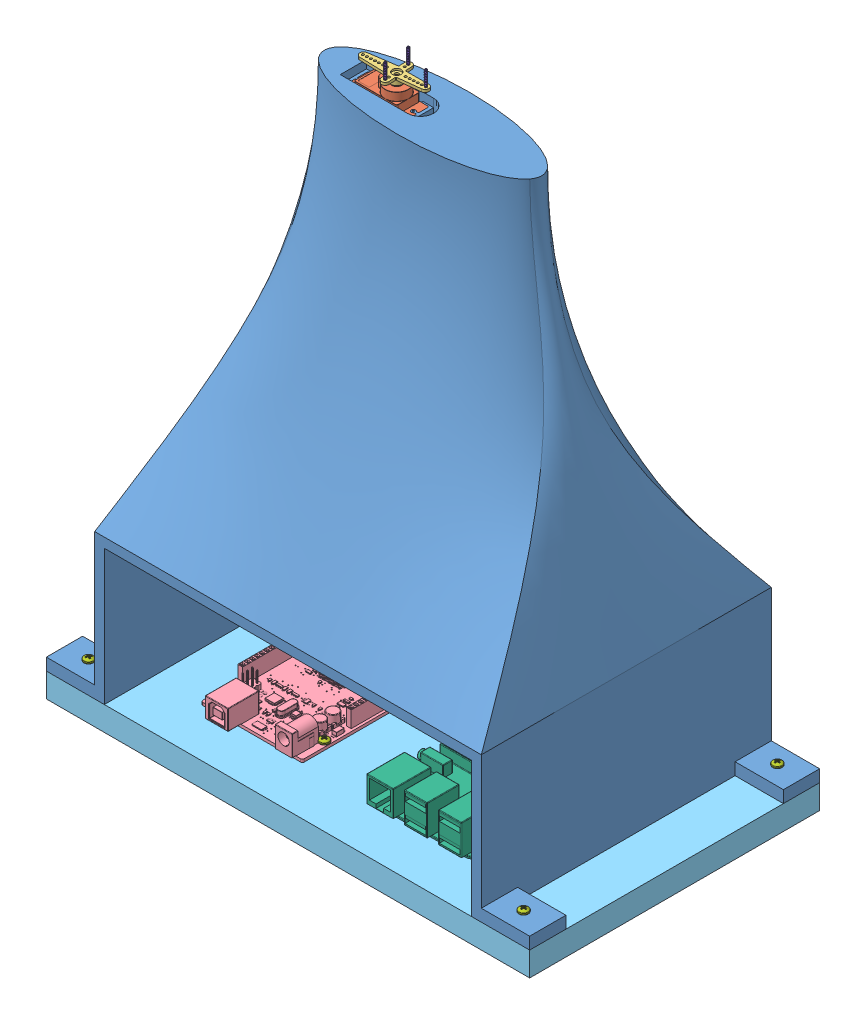
SolidWorks assembly Arm_Assembly, configuration Défaut. Lengths in mm.
Overall size (254 309.43 152.4).
24 component instances, 8 part files, 47 mates.
Components (placement in the parent):
- Bras-1: Bras [Défaut] at (-45.4509 154.1913 381.0005) size (254 279.4 152.4)
- SG90 - Micro Servo Assembly Socle-3: SG90 - Micro Servo Assembly Socle [Default] at (-69.6506 142.242 381.0005) x (-1 0 0) z (0 0 -1) size (37.72 31.75 18.74) (flexible)
  - SG90 - Micro Servo 9g - Tower Pro.1-2: SG90 - Micro Servo 9g - Tower Pro.1 [Peça] at origin size (32.1 29.95 12.4)
  - SG90 - Micro Servo 9g - Tower Pro.4-1: SG90 - Micro Servo 9g - Tower Pro.4 [Peça] at (-5.15 21.1 0) x (0.998205 0 -0.059895) z (0.059895 0 0.998205) size (34.5 3.8 16.7)
- arduinoMega-1: arduinoMega [Detailed] at (-89.9209 -125.2087 382.3105) x (0 0 -1) z (1 0 0) size (108.32 14.5 53.3)
- Base-1: Base [Défaut] at (-172.4509 -137.9087 457.2005) size (254 12.7 152.4)
- Raspberrypimodel-1: Raspberrypimodel [Default] at (1.1691 -125.2087 389.3005) x (0 0 1) z (-1 0 0) size (87.5 17 58)
- 92000A106_18-8 SS METRIC PAN HEAD PHIL MACHINE SCREW-1: 92000A106_18-8 SS METRIC PAN HEAD PHIL MACHINE SCREW [92000A106] at (-65.8109 -133.7087 335.3305) x (1 0 0) z (0 1 0) size (5 5 12.1)
- 92000A106_18-8 SS METRIC PAN HEAD PHIL MACHINE SCREW-4: 92000A106_18-8 SS METRIC PAN HEAD PHIL MACHINE SCREW [92000A106] at (22.1691 -134.2087 407.8005) x (1 0 0) z (0 1 0) size (5 5 12.1)
- 92000A106_18-8 SS METRIC PAN HEAD PHIL MACHINE SCREW-5: 92000A106_18-8 SS METRIC PAN HEAD PHIL MACHINE SCREW [92000A106] at (-26.8309 -134.2087 350.3005) x (1 0 0) z (0 1 0) size (5 5 12.1)
- 92000A106_18-8 SS METRIC PAN HEAD PHIL MACHINE SCREW-6: 92000A106_18-8 SS METRIC PAN HEAD PHIL MACHINE SCREW [92000A106] at (22.1691 -134.2087 350.3005) x (1 0 0) z (0 1 0) size (5 5 12.1)
- 92000A106_18-8 SS METRIC PAN HEAD PHIL MACHINE SCREW-7: 92000A106_18-8 SS METRIC PAN HEAD PHIL MACHINE SCREW [92000A106] at (-65.8109 -133.7087 417.8005) x (1 0 0) z (0 1 0) size (5 5 12.1)
- 92000A106_18-8 SS METRIC PAN HEAD PHIL MACHINE SCREW-8: 92000A106_18-8 SS METRIC PAN HEAD PHIL MACHINE SCREW [92000A106] at (-26.8309 -134.2087 408.3005) x (1 0 0) z (0 1 0) size (5 5 12.1)
- 92000A106_18-8 SS METRIC PAN HEAD PHIL MACHINE SCREW-9: 92000A106_18-8 SS METRIC PAN HEAD PHIL MACHINE SCREW [92000A106] at (-70.8909 -133.7087 365.7805) x (1 0 0) z (0 1 0) size (5 5 12.1)
- 92000A106_18-8 SS METRIC PAN HEAD PHIL MACHINE SCREW-10: 92000A106_18-8 SS METRIC PAN HEAD PHIL MACHINE SCREW [92000A106] at (-98.8009 -133.7087 365.7805) x (1 0 0) z (0 1 0) size (5 5 12.1)
- 92000A106_18-8 SS METRIC PAN HEAD PHIL MACHINE SCREW-11: 92000A106_18-8 SS METRIC PAN HEAD PHIL MACHINE SCREW [92000A106] at (-114.0309 -133.7087 416.5705) x (1 0 0) z (0 1 0) size (5 5 12.1)
- 92000A106_18-8 SS METRIC PAN HEAD PHIL MACHINE SCREW-12: 92000A106_18-8 SS METRIC PAN HEAD PHIL MACHINE SCREW [92000A106] at (68.8491 -128.8587 447.6755) x (1 0 0) z (0 1 0) size (5 5 12.1)
- 92000A106_18-8 SS METRIC PAN HEAD PHIL MACHINE SCREW-13: 92000A106_18-8 SS METRIC PAN HEAD PHIL MACHINE SCREW [92000A106] at (-159.7509 -128.8587 447.6755) x (0.383452 0 -0.923561) z (0 1 0) size (5 5 12.1)
- 92000A106_18-8 SS METRIC PAN HEAD PHIL MACHINE SCREW-14: 92000A106_18-8 SS METRIC PAN HEAD PHIL MACHINE SCREW [92000A106] at (68.8491 -128.8587 314.3255) x (1 0 0) z (0 1 0) size (5 5 12.1)
- 92000A106_18-8 SS METRIC PAN HEAD PHIL MACHINE SCREW-15: 92000A106_18-8 SS METRIC PAN HEAD PHIL MACHINE SCREW [92000A106] at (-159.7509 -128.8587 314.3255) x (-0.837169 0 -0.546944) z (0 1 0) size (5 5 12.1)
- 92000A106_18-8 SS METRIC PAN HEAD PHIL MACHINE SCREW-16: 92000A106_18-8 SS METRIC PAN HEAD PHIL MACHINE SCREW [92000A106] at (-114.0309 -133.7087 341.6905) x (1 0 0) z (0 1 0) size (5 5 12.1)
- 92453A856_BRASS ROUND HEAD SLOTTED MACHINE SCREW-1: 92453A856_BRASS ROUND HEAD SLOTTED MACHINE SCREW [92453A856] at (-64.8869 161.942 374.5621) x (1 0 0) z (0 -1 0) size (2.18 2.18 10.63)
- 92453A856_BRASS ROUND HEAD SLOTTED MACHINE SCREW-2: 92453A856_BRASS ROUND HEAD SLOTTED MACHINE SCREW [92453A856] at (-64.1142 161.942 387.4389) x (1 0 0) z (0 -1 0) size (2.18 2.18 10.63)
- 92453A856_BRASS ROUND HEAD SLOTTED MACHINE SCREW-3: 92453A856_BRASS ROUND HEAD SLOTTED MACHINE SCREW [92453A856] at (-50.0765 161.942 380.135) x (1 0 0) z (0 -1 0) size (2.18 2.18 10.63)
Mates (geometry in assembly coordinates):
- Coaxiale1: concentric aligned: circle of Bras-1; circle of SG90 - Micro Servo Assembly Socle-3/SG90 - Micro Servo 9g - Tower Pro.1-2
- Coaxiale4: concentric aligned: circle of Bras-1; circle of SG90 - Micro Servo Assembly Socle-3/SG90 - Micro Servo 9g - Tower Pro.1-2
- Coïncidente1: coincident anti-aligned: plane of Bras-1 through (-45.4509 131.692 381.0005) normal (0 1 0); plane of SG90 - Micro Servo Assembly Socle-3/SG90 - Micro Servo 9g - Tower Pro.1-2 through (-59.2506 131.692 375.7505) normal (0 -1 0)
- Coïncidente2: coincident anti-aligned: plane of Bras-1 through (-45.4509 -125.2087 381.0005) normal (0 -1 0); plane of Base-1 through (-172.4509 -125.2087 457.2005) normal (0 1 0)
- Coïncidente3: coincident aligned: plane of Bras-1 through (-172.4509 -118.8587 304.8005) normal (-1 0 0); plane of Base-1 through (-172.4509 -125.2087 457.2005) normal (-1 0 0)
- Coïncidente4: coincident aligned: plane of Bras-1 through (-45.4509 154.1913 304.8005) normal (0 0 -1); plane of Base-1 through (-172.4509 -125.2087 304.8005) normal (0 0 -1)
- Coïncidente5: coincident anti-aligned: plane of Raspberrypimodel-1 through (1.1691 -125.2087 389.3005) normal (0 -1 0); plane of Base-1 through (-172.4509 -125.2087 457.2005) normal (0 1 0)
- Coïncidente6: coincident anti-aligned: plane of arduinoMega-1 through (-89.9209 -125.2087 382.3105) normal (0 -1 0); plane of Base-1 through (-172.4509 -125.2087 457.2005) normal (0 1 0)
- Parallèle1: parallel aligned: plane of Bras-1 through (-141.9709 154.1913 381.0005) normal (1 0 0); plane of Raspberrypimodel-1 through (22.6691 -108.2087 417.3005) normal (1 0 0)
- Parallèle2: parallel anti-aligned: plane of Bras-1 through (51.0691 154.1913 381.0005) normal (-1 0 0); plane of arduinoMega-1 through (-64.6209 -115.2087 359.1005) normal (1 0 0)
- Distance4: distance = 25.4 mm: line of arduinoMega-1 through (-115.5709 -125.2087 431.8005) axis (1 0 0); line of Base-1 through (-172.4509 -125.2087 457.2005) axis (1 0 0)
- Distance5: distance = 25.4 mm anti-aligned: plane of Bras-1 through (-141.9709 154.1913 381.0005) normal (1 0 0); plane of arduinoMega-1 through (-116.5709 -123.7087 431.8005) normal (-1 0 0)
- Coaxiale7: concentric anti-aligned: circle of Base-1; circle of Raspberrypimodel-1
- Coaxiale8: concentric aligned: circle of Bras-1; circle of 92000A106_18-8 SS METRIC PAN HEAD PHIL MACHINE SCREW-15
- Coïncidente12: coincident aligned: plane of Bras-1 through (-45.4509 -118.8587 381.0005) normal (0 1 0); circle of 92000A106_18-8 SS METRIC PAN HEAD PHIL MACHINE SCREW-15
- Coaxiale9: concentric aligned: circle of Bras-1; circle of 92000A106_18-8 SS METRIC PAN HEAD PHIL MACHINE SCREW-13
- Coïncidente14: coincident anti-aligned: plane of Bras-1 through (-45.4509 -118.8587 381.0005) normal (0 1 0); plane of 92000A106_18-8 SS METRIC PAN HEAD PHIL MACHINE SCREW-13 through (-159.7509 -118.8587 447.6755) normal (0 -1 0)
- Coïncidente15: coincident anti-aligned: plane of Bras-1 through (-45.4509 -118.8587 381.0005) normal (0 1 0); plane of 92000A106_18-8 SS METRIC PAN HEAD PHIL MACHINE SCREW-14 through (68.8491 -118.8587 314.3255) normal (0 -1 0)
- Coaxiale10: concentric aligned: circle of Bras-1; circle of 92000A106_18-8 SS METRIC PAN HEAD PHIL MACHINE SCREW-14
- Coïncidente16: coincident anti-aligned: plane of Bras-1 through (-45.4509 -118.8587 381.0005) normal (0 1 0); plane of 92000A106_18-8 SS METRIC PAN HEAD PHIL MACHINE SCREW-12 through (68.8491 -118.8587 447.6755) normal (0 -1 0)
- Coaxiale11: concentric aligned: circle of Bras-1; circle of 92000A106_18-8 SS METRIC PAN HEAD PHIL MACHINE SCREW-12
- Coïncidente17: coincident anti-aligned: plane of arduinoMega-1 through (-89.9209 -123.7087 382.3105) normal (0 1 0); plane of 92000A106_18-8 SS METRIC PAN HEAD PHIL MACHINE SCREW-11 through (-114.0309 -123.7087 416.5705) normal (0 -1 0)
- Coïncidente18: coincident anti-aligned: plane of arduinoMega-1 through (-89.9209 -123.7087 382.3105) normal (0 1 0); plane of 92000A106_18-8 SS METRIC PAN HEAD PHIL MACHINE SCREW-1 through (-65.8109 -123.7087 335.3305) normal (0 -1 0)
- Coïncidente19: coincident anti-aligned: plane of arduinoMega-1 through (-89.9209 -123.7087 382.3105) normal (0 1 0); plane of 92000A106_18-8 SS METRIC PAN HEAD PHIL MACHINE SCREW-9 through (-70.8909 -123.7087 365.7805) normal (0 -1 0)
- Coïncidente20: coincident anti-aligned: plane of arduinoMega-1 through (-89.9209 -123.7087 382.3105) normal (0 1 0); plane of 92000A106_18-8 SS METRIC PAN HEAD PHIL MACHINE SCREW-7 through (-65.8109 -123.7087 417.8005) normal (0 -1 0)
- Coïncidente21: coincident anti-aligned: plane of arduinoMega-1 through (-89.9209 -123.7087 382.3105) normal (0 1 0); plane of 92000A106_18-8 SS METRIC PAN HEAD PHIL MACHINE SCREW-10 through (-98.8009 -123.7087 365.7805) normal (0 -1 0)
- Coïncidente22: coincident anti-aligned: plane of arduinoMega-1 through (-89.9209 -123.7087 382.3105) normal (0 1 0); plane of 92000A106_18-8 SS METRIC PAN HEAD PHIL MACHINE SCREW-16 through (-114.0309 -123.7087 341.6905) normal (0 -1 0)
- Coaxiale12: concentric aligned: circle of arduinoMega-1; circle of 92000A106_18-8 SS METRIC PAN HEAD PHIL MACHINE SCREW-11
- Coaxiale13: concentric aligned: circle of arduinoMega-1; circle of 92000A106_18-8 SS METRIC PAN HEAD PHIL MACHINE SCREW-10
- Coaxiale14: concentric aligned: circle of arduinoMega-1; circle of 92000A106_18-8 SS METRIC PAN HEAD PHIL MACHINE SCREW-9
- Coaxiale15: concentric aligned: circle of arduinoMega-1; circle of 92000A106_18-8 SS METRIC PAN HEAD PHIL MACHINE SCREW-7
- Coaxiale16: concentric aligned: circle of arduinoMega-1; circle of 92000A106_18-8 SS METRIC PAN HEAD PHIL MACHINE SCREW-1
- Coaxiale17: concentric aligned: circle of arduinoMega-1; circle of 92000A106_18-8 SS METRIC PAN HEAD PHIL MACHINE SCREW-16
- Coïncidente23: coincident anti-aligned: plane of Raspberrypimodel-1 through (1.1691 -124.2087 389.3005) normal (0 1 0); plane of 92000A106_18-8 SS METRIC PAN HEAD PHIL MACHINE SCREW-5 through (-26.8309 -124.2087 350.3005) normal (0 -1 0)
- Coïncidente24: coincident anti-aligned: plane of Raspberrypimodel-1 through (1.1691 -124.2087 389.3005) normal (0 1 0); plane of 92000A106_18-8 SS METRIC PAN HEAD PHIL MACHINE SCREW-6 through (22.1691 -124.2087 350.3005) normal (0 -1 0)
- Coïncidente25: coincident anti-aligned: plane of Raspberrypimodel-1 through (1.1691 -124.2087 389.3005) normal (0 1 0); plane of 92000A106_18-8 SS METRIC PAN HEAD PHIL MACHINE SCREW-8 through (-26.8309 -124.2087 408.3005) normal (0 -1 0)
- Coïncidente26: coincident anti-aligned: plane of Raspberrypimodel-1 through (1.1691 -124.2087 389.3005) normal (0 1 0); plane of 92000A106_18-8 SS METRIC PAN HEAD PHIL MACHINE SCREW-4 through (22.1691 -124.2087 407.8005) normal (0 -1 0)
- Coaxiale18: concentric anti-aligned: circle of Raspberrypimodel-1; circle of 92000A106_18-8 SS METRIC PAN HEAD PHIL MACHINE SCREW-8
- Coaxiale19: concentric aligned: circle of Raspberrypimodel-1; circle of 92000A106_18-8 SS METRIC PAN HEAD PHIL MACHINE SCREW-4
- Coaxiale20: concentric anti-aligned: circle of Raspberrypimodel-1; circle of 92000A106_18-8 SS METRIC PAN HEAD PHIL MACHINE SCREW-6
- Coaxiale21: concentric anti-aligned: circle of Raspberrypimodel-1; circle of 92000A106_18-8 SS METRIC PAN HEAD PHIL MACHINE SCREW-5
- Coïncidente28: coincident anti-aligned: plane of SG90 - Micro Servo Assembly Socle-3/SG90 - Micro Servo 9g - Tower Pro.4-1 through (-64.5006 161.942 381.0005) normal (0 -1 0); plane of 92453A856_BRASS ROUND HEAD SLOTTED MACHINE SCREW-2 through (-64.1142 161.942 387.4389) normal (0 1 0)
- Coaxiale22: concentric aligned: circle of SG90 - Micro Servo Assembly Socle-3/SG90 - Micro Servo 9g - Tower Pro.4-1; circle of 92453A856_BRASS ROUND HEAD SLOTTED MACHINE SCREW-2
- Coïncidente29: coincident anti-aligned: plane of SG90 - Micro Servo Assembly Socle-3/SG90 - Micro Servo 9g - Tower Pro.4-1 through (-64.5006 161.942 381.0005) normal (0 -1 0); plane of 92453A856_BRASS ROUND HEAD SLOTTED MACHINE SCREW-3 through (-50.0765 161.942 380.135) normal (0 1 0)
- Coïncidente30: coincident anti-aligned: plane of SG90 - Micro Servo Assembly Socle-3/SG90 - Micro Servo 9g - Tower Pro.4-1 through (-64.5006 161.942 381.0005) normal (0 -1 0); plane of 92453A856_BRASS ROUND HEAD SLOTTED MACHINE SCREW-1 through (-64.8869 161.942 374.5621) normal (0 1 0)
- Coaxiale23: concentric aligned: circle of SG90 - Micro Servo Assembly Socle-3/SG90 - Micro Servo 9g - Tower Pro.4-1; circle of 92453A856_BRASS ROUND HEAD SLOTTED MACHINE SCREW-3
- Coaxiale24: concentric aligned: circle of SG90 - Micro Servo Assembly Socle-3/SG90 - Micro Servo 9g - Tower Pro.4-1; circle of 92453A856_BRASS ROUND HEAD SLOTTED MACHINE SCREW-1
